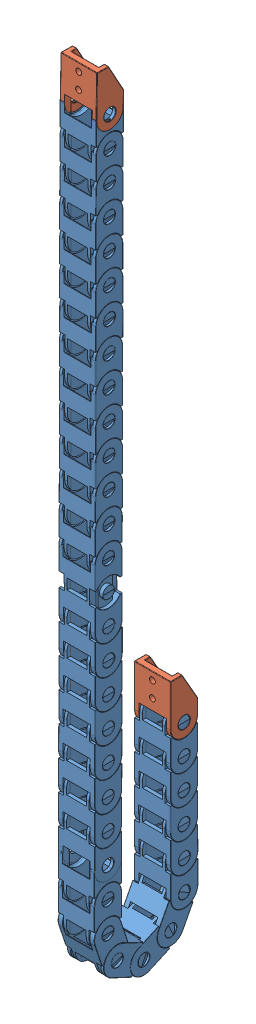
SolidWorks assembly Cable Drag Chain Wire R18 10x15mm, configuration Valor predeterminado. Lengths in mm.
Overall size (18.81 416.43 57.67).
35 component instances, 2 part files, 0 mates.
Components (placement in the parent):
- esteira 15mm meio-1: esteira 15mm meio [Valor predeterminado] at (-22.3167 -507.0546 64.5156) x (-1 0 0) z (0 0.317305 -0.948324) size (18.71 29.17 14)
- esteira 15mm ponta-1: esteira 15mm ponta [Valor predeterminado] at (-22.318 -416.2069 27.9391) x (1 0 0) z (0 0 -1) size (18.71 28.52 14)
- esteira 15mm meio-2: esteira 15mm meio [Valor predeterminado] at (-22.3387 -509.5632 37.8653) x (1 0 0) z (0 -0.913545 -0.406737) size (18.71 29.17 14)
- esteira 15mm meio-3: esteira 15mm meio [Valor predeterminado] at (-22.3146 -369.2468 66.7297) x (1 0 0) z (0 0 -1) size (18.71 29.17 14)
- esteira 15mm meio-4: esteira 15mm meio [Valor predeterminado] at (-22.3271 -445.1475 67.0383) x (1 0 0) z (0 0 -1) size (18.71 29.17 14)
- esteira 15mm meio-5: esteira 15mm meio [Valor predeterminado] at (-22.3222 -503.0373 30.6766) x (1 0 0) z (0 -0.461749 -0.887011) size (18.71 29.17 14)
- esteira 15mm meio-6: esteira 15mm meio [Valor predeterminado] at (-22.334 -476.8932 27.8842) x (1 0 0) z (0 0.008727 -0.999962) size (18.71 29.17 14)
- esteira 15mm meio-7: esteira 15mm meio [Valor predeterminado] at (-22.3341 -509.1784 45.7998) x (1 0 0) z (0 -0.906308 0.422618) size (18.71 29.17 14)
- esteira 15mm meio-8: esteira 15mm meio [Valor predeterminado] at (-22.3247 -322.9926 52.7684) x (1 0 0) z (0 0.008727 0.999962) size (18.71 29.17 14)
- esteira 15mm meio-9: esteira 15mm meio [Valor predeterminado] at (-22.3384 -307.7895 52.6373) x (1 0 0) z (0 0.008727 0.999962) size (18.71 29.17 14)
- esteira 15mm meio-11: esteira 15mm meio [Valor predeterminado] at (-22.3209 -262.1913 52.5803) size (18.71 29.17 14)
- esteira 15mm meio-12: esteira 15mm meio [Valor predeterminado] at (-22.3466 -231.8827 52.4074) x (1 0 0) z (0 0.008727 0.999962) size (18.71 29.17 14)
- esteira 15mm meio-13: esteira 15mm meio [Valor predeterminado] at (-22.3232 -490.0658 53.1222) size (18.71 29.17 14)
- esteira 15mm meio-14: esteira 15mm meio [Valor predeterminado] at (-22.324 -277.3762 52.553) size (18.71 29.17 14)
- esteira 15mm meio-15: esteira 15mm meio [Valor predeterminado] at (-22.3388 -201.4377 52.4327) size (18.71 29.17 14)
- esteira 15mm meio-16: esteira 15mm meio [Valor predeterminado] at (-22.3225 -474.8675 53.1249) size (18.71 29.17 14)
- esteira 15mm meio-17: esteira 15mm meio [Valor predeterminado] at (-22.3279 -247.0151 52.5574) size (18.71 29.17 14)
- esteira 15mm meio-18: esteira 15mm meio [Valor predeterminado] at (-22.3256 -292.5631 52.5622) size (18.71 29.17 14)
- esteira 15mm meio-19: esteira 15mm meio [Valor predeterminado] at (-22.3305 -216.6139 52.4266) size (18.71 29.17 14)
- esteira 15mm meio-20: esteira 15mm meio [Valor predeterminado] at (-22.3221 -171.0879 52.3443) x (1 0 0) z (0 0.008727 0.999962) size (18.71 29.17 14)
- esteira 15mm meio-21: esteira 15mm meio [Valor predeterminado] at (-22.3231 -186.249 52.4208) size (18.71 29.17 14)
- esteira 15mm meio-22: esteira 15mm meio [Valor predeterminado] at (-22.322 -338.1238 52.8394) size (18.71 29.17 14)
- esteira 15mm meio-25: esteira 15mm meio [Valor predeterminado] at (-22.3119 -460.2865 67.0334) x (1 0 0) z (0 0 -1) size (18.71 29.17 14)
- esteira 15mm meio-27: esteira 15mm meio [Valor predeterminado] at (-22.3231 -140.6384 52.1621) size (18.71 29.17 14)
- esteira 15mm meio-29: esteira 15mm meio [Valor predeterminado] at (-22.3273 -155.8576 52.2339) size (18.71 29.17 14)
- esteira 15mm meio-30: esteira 15mm meio [Valor predeterminado] at (-22.3109 -429.8908 66.979) x (1 0 0) z (0 -0.008727 -0.999962) size (18.71 29.17 14)
- esteira 15mm meio-31: esteira 15mm meio [Valor predeterminado] at (-22.3151 -492.0091 27.848) x (1 0 0) z (0 0 -1) size (18.71 29.17 14)
- esteira 15mm meio-32: esteira 15mm meio [Valor predeterminado] at (-22.4083 -399.6094 66.7522) x (1 0 0) z (0 0 -1) size (18.71 29.17 14)
- esteira 15mm meio-33: esteira 15mm meio [Valor predeterminado] at (-22.3793 -461.6635 27.9322) x (1 0 0) z (0 0 -1) size (18.71 29.17 14)
- esteira 15mm meio-35: esteira 15mm meio [Valor predeterminado] at (-22.3359 -354.0632 66.7442) x (1 0 0) z (0 0 -1) size (18.71 29.17 14)
- esteira 15mm meio-36: esteira 15mm meio [Valor predeterminado] at (-22.3849 -414.7375 66.8364) x (1 0 0) z (0 -0.008727 -0.999962) size (18.71 29.17 14)
- esteira 15mm meio-37: esteira 15mm meio [Valor predeterminado] at (-22.3863 -384.4394 66.7373) x (1 0 0) z (0 0 -1) size (18.71 29.17 14)
- esteira 15mm meio-39: esteira 15mm meio [Valor predeterminado] at (-22.318 -431.334 27.9604) x (1 0 0) z (0 0 -1) size (18.71 29.17 14)
- esteira 15mm meio-40: esteira 15mm meio [Valor predeterminado] at (-22.3238 -446.5058 27.9472) x (1 0 0) z (0 0 -1) size (18.71 29.17 14)
- esteira 15mm ponta-2: esteira 15mm ponta [Valor predeterminado] at (-22.3155 -125.9961 66.0136) x (1 0 0) z (0 -0.017452 -0.999848) size (18.71 28.52 14)
